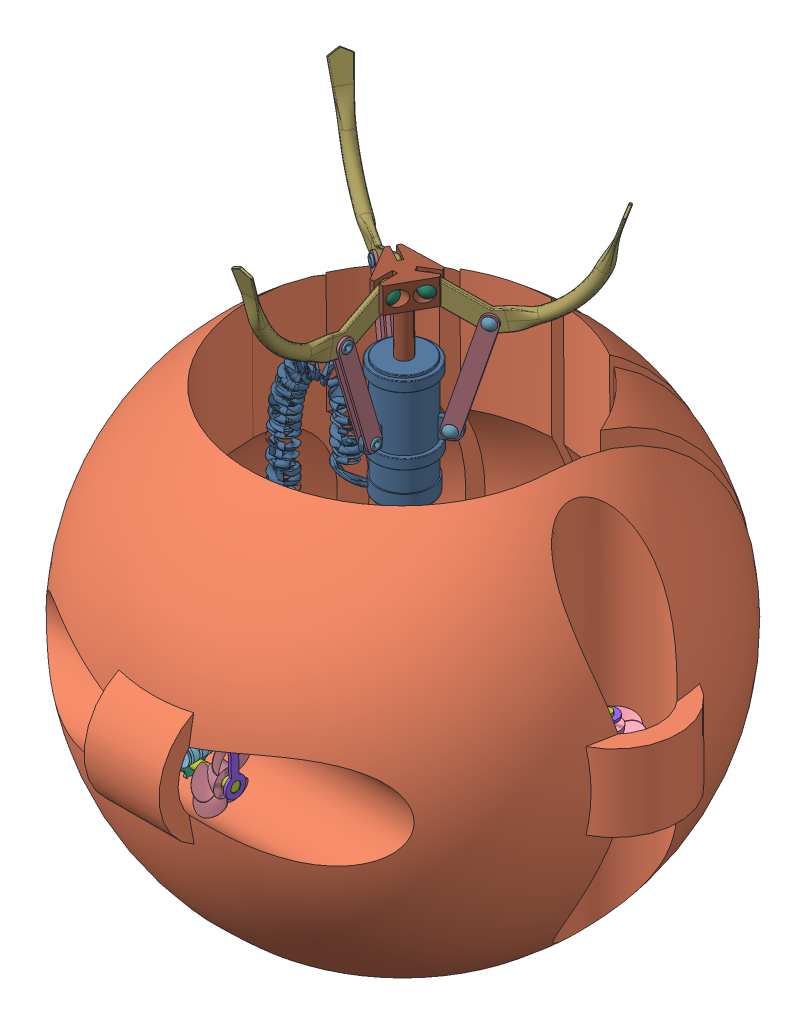
SolidWorks assembly Ensamblaje3, configuration Predeterminado. Lengths in mm.
Overall size (450.55 570.04 429.3).
49 component instances, 15 part files, 26 mates.
Components (placement in the parent):
- Pieza2-1: Pieza2 [Predeterminado] at (-34.488 253.5547 130.2507) x (0.999885 0.01398 -0.005873) z (-0.005729 -0.010275 -0.999931) size (100 100 125)
- esfera-1: esfera [Predeterminado] at (14.9319 234.6332 182.7818) x (0.014039 -0.999849 0.010193) z (0.012601 -0.010017 -0.99987) size (380 440 420)
- Ejes 1-1: Ejes 1 [Predeterminado] at (16.7137 233.883 180.6556) x (0.014039 -0.999849 0.010193) z (0.015814 0.010415 0.999821) size (260 360 184.4)
- Pieza5-1: Pieza5 [Predeterminado] at (36.17 225.0744 353.282) x (0.012182 0.006562 -0.999904) z (0.999904 -0.006643 0.012138) size (49.17 48.96 11.21)
- worm-1: worm [Predeterminado] at (19.7723 236.3191 345.1076) x (0.999875 -0.000209 -0.015813) z (0.015814 0.010415 0.999821) size (16 16.41 26.33)
- gear-1: gear [Predeterminado] at (18.4041 225.247 352.8856) x (0.013028 0.747503 -0.66413) z (0.999904 -0.006643 0.012139) size (19.79 19.79 2)
- Pieza5-2: Pieza5 [Predeterminado] at (-159.6974 247.0657 172.1305) x (0.994038 0.012854 -0.108278) z (-0.014039 0.999849 -0.010193) size (49.17 48.96 11.21)
- Pieza5-3: Pieza5 [Predeterminado] at (188.989 257.8641 195.2969) x (0.817754 0.017348 0.575307) z (0.01404 -0.999849 0.010194) size (49.17 48.96 11.21)
- Pieza5-4: Pieza5 [Predeterminado] at (9.1875 59.5186 198.0938) x (0.986717 0.162088 0.010811) z (-0.0126 0.010017 0.99987) size (49.17 48.96 11.21)
- gear-2: gear [Predeterminado] at (9.1409 59.5957 192.1886) x (0.999921 0.000063 0.012601) z (-0.012601 0.010017 0.99987) size (19.79 19.79 2)
- gear-3: gear [Predeterminado] at (-159.708 233.7543 171.9082) x (0.999805 0.013896 -0.014039) z (0.014039 -0.999849 0.010193) size (19.79 19.79 2)
- gear-4: gear [Predeterminado] at (188.6888 238.5905 194.9996) x (0.999805 0.013896 -0.014039) z (0.014039 -0.999849 0.010193) size (19.79 19.79 2)
- worm-2: worm [Predeterminado] at (181.8244 235.5931 178.8867) x (-0.015758 -0.014382 -0.999772) z (0.999776 0.013876 -0.015958) size (16 16.41 26.33)
- worm-4: worm [Predeterminado] at (-148.8559 232.9027 183.3553) x (0.01593 0.002169 0.999871) z (-0.999776 -0.013876 0.015958) size (16 16.41 26.33)
- worm-5: worm [Predeterminado] at (18.3543 74.6912 183.1674) x (0.848002 0.017308 0.52971) z (0.014039 -0.999849 0.010193) size (16 16.41 26.33)
- mini eje-1: mini eje [Predeterminado] at (188.7869 266.4229 195.1489) x (0.09265 -0.00885 -0.995659) z (0.014039 -0.999849 0.010193) size (8 8 60)
- sujeta mini eje-1: sujeta mini eje [Predeterminado] at (189.066 218.1565 195.1952) x (-0.013575 0.010003 0.999858) z (0.014039 -0.999849 0.010193) size (16 56.94 2)
- sujeta mini eje-2: sujeta mini eje [Predeterminado] at (189.5811 264.863 195.6103) x (0.02299 0.010515 0.99968) z (0.014039 -0.999849 0.010193) size (16 56.94 2)
- sujeta mini eje-3: sujeta mini eje [Predeterminado] at (-159.6349 205.6977 171.876) x (0.026481 -0.000282 -0.999649) z (-0.003497 -0.999994 0.000189) size (16 56.94 2)
- mini eje-2: mini eje [Predeterminado] at (-159.8585 202.3436 171.8952) x (0.901561 -0.003071 0.43264) z (0.003497 0.999994 -0.000189) size (8 8 60)
- sujeta mini eje-4: sujeta mini eje [Predeterminado] at (-159.8363 261.8256 171.9609) x (-0.025639 0.000279 0.999671) z (0.003497 0.999994 -0.000189) size (16 56.94 2)
- mini eje-3: mini eje [Predeterminado] at (9.153 59.6706 153.774) size (8 8 60)
- sujeta mini eje-5: sujeta mini eje [Predeterminado] at (9.2734 59.7371 155.3243) size (16 56.94 2)
- sujeta mini eje-6: sujeta mini eje [Predeterminado] at (9.1464 59.7862 211.2607) size (16 56.94 2)
- bateria-1: bateria [Predeterminado] at (14.3008 144.5079 182.0033) x (0.300394 -0.005506 -0.953799) z (0.014039 -0.999849 0.010193) size (200 200 30)
- mini eje-4: mini eje [Predeterminado] at (-7.5921 225.1294 353.1829) x (-0.004864 -0.442554 -0.896729) z (0.999976 0.002338 -0.006578) size (8 8 60)
- sujeta mini eje-7: sujeta mini eje [Predeterminado] at (-4.8348 225.2894 353.3905) x (-0.006596 0.007693 -0.999949) z (0.999976 0.002338 -0.006578) size (16 56.94 2)
- sujeta mini eje-8: sujeta mini eje [Predeterminado] at (51.0332 225.0668 353.0596) x (-0.006643 0.02898 -0.999558) z (0.999976 0.002338 -0.006578) size (16 56.94 2)
- claw game grabber-1: claw game grabber [Predeterminado] at (16.4487 365.3089 183.0189) x (0.999805 0.013896 -0.014039) z (0.014039 -0.999849 0.010193) size (253.22 219.29 319.04)
  - case-1: case [Predeterminado] at origin size (110.45 77.76 160.33)
  - piston-1: piston [Predeterminado] at (0 0 -92.0003) size (43.11 37.33 100)
  - claw-1: claw [Predeterminado] at (0 14.5 -102.0003) x (1 0 0) z (0 -0.445532 0.895266) size (16.03 91.28 125.86)
  - claw-2: claw [Predeterminado] at (-12.5574 -7.25 -102.0003) x (-0.5 0.866025 0) z (0.385842 0.222766 0.895266) size (16.03 91.28 125.86)
  - claw-3: claw [Predeterminado] at (12.5574 -7.25 -102.0003) x (-0.5 -0.866025 0) z (-0.385842 0.222766 0.895266) size (16.03 91.28 125.86)
  - strut-1: strut [Predeterminado] at (3 27.5 -7.5) x (1 0 0) z (0 -0.285133 0.958488) size (2 12 92)
  - strut-2: strut [Predeterminado] at (-3 27.5 -7.5) x (1 0 0) z (0 -0.285133 0.958488) size (2 12 92)
  - strut-3: strut [Predeterminado] at (22.3157 -16.3481 -7.5) x (-0.5 -0.866025 0) z (-0.246932 0.142566 0.958488) size (2 12 92)
  - strut-4: strut [Predeterminado] at (25.3157 -11.1519 -7.5) x (-0.5 -0.866025 0) z (-0.246932 0.142566 0.958488) size (2 12 92)
  - strut-5: strut [Predeterminado] at (-25.3157 -11.1519 -7.5) x (-0.5 0.866025 0) z (0.246932 0.142566 0.958488) size (2 12 92)
  - strut-6: strut [Predeterminado] at (-22.3157 -16.3481 -7.5) x (-0.5 0.866025 0) z (0.246932 0.142566 0.958488) size (2 12 92)
  - rivet-1: rivet [Predeterminado] at (23.8157 -13.75 -7.5) x (0.866025 -0.5 0) z (0 0 1) size (11.39 14.58 11.86)
  - rivet-2: rivet [Predeterminado] at (43.5703 -25.1553 -84.179) x (0.866025 -0.5 0) z (0 0 1) size (11.39 14.58 11.86)
  - rivet-3: rivet [Predeterminado] at (0 27.5 -7.5) x (0 1 0) z (0 0 1) size (11.39 14.58 11.86)
  - rivet-4: rivet [Predeterminado] at (0 50.3106 -84.179) x (0 1 0) z (0 0 1) size (11.39 14.58 11.86)
  - rivet-5: rivet [Predeterminado] at (-23.8157 -13.75 -7.5) x (-0.866025 -0.5 0) z (0 0 1) size (11.39 14.58 11.86)
  - rivet-6: rivet [Predeterminado] at (-43.5703 -25.1553 -84.179) x (-0.866025 -0.5 0) z (0 0 1) size (11.39 14.58 11.86)
  - rivet_2-1: rivet_2 [Predeterminado] at (0 14.5 -102.0003) size (22.19 14.92 14.32)
  - rivet_2-2: rivet_2 [Predeterminado] at (12.5574 -7.25 -102.0003) x (0.5 0.866025 0) z (0 0 1) size (22.19 14.92 14.32)
  - rivet_2-3: rivet_2 [Predeterminado] at (-12.5574 -7.25 -102.0003) x (0.5 -0.866025 0) z (0 0 1) size (22.19 14.92 14.32)
Mates (geometry in assembly coordinates):
- Paralelo1: parallel aligned: cylinder of Pieza2-1 through (15.7927 254.7674 179.9536) axis (0.014039 -0.999849 0.010193) radius 4; cylinder of Ejes 1-1 through (15.5905 313.871 179.8401) axis (0.014039 -0.999849 0.010193) radius 4
- Paralelo2: parallel anti-aligned: cylinder of esfera-1 through (11.0992 507.5921 179.999) axis (0.014039 -0.999849 0.010193) radius 120; cylinder of Ejes 1-1 through (19.2408 53.9101 182.4904) axis (-0.014039 0.999849 -0.010193) radius 4
- Paralelo3: parallel anti-aligned: cylinder of esfera-1 through (11.0992 507.5921 179.999) axis (0.014039 -0.999849 0.010193) radius 120; cylinder of Ejes 1-1 through (19.2408 53.9101 182.4904) axis (-0.014039 0.999849 -0.010193) radius 4
- Paralelo4: parallel aligned: cylinder of Pieza2-1 through (15.7927 254.7674 179.9536) axis (0.014039 -0.999849 0.010193) radius 4; cylinder of Ejes 1-1 through (15.5905 313.871 179.8401) axis (0.014039 -0.999849 0.010193) radius 4
- Paralelo5: parallel aligned: cylinder of Ejes 1-1 through (19.5603 235.7578 360.6233) axis (-0.015814 -0.010415 -0.999821) radius 4; cylinder of worm-1 through (20.0885 236.5274 365.104) axis (-0.015814 -0.010415 -0.999821) radius 4
- Paralelo6: parallel aligned: cylinder of Pieza5-1 through (46.7728 225.004 353.4107) axis (-0.999904 0.006643 -0.012139) radius 4.2654; cylinder of gear-1 through (20.4039 225.2337 352.9099) axis (-0.999904 0.006643 -0.012139) radius 4
- Paralelo7: parallel aligned: cylinder of Pieza5-1 through (46.7728 225.004 353.4107) axis (-0.999904 0.006643 -0.012139) radius 4.2654; cylinder of gear-1 through (20.4039 225.2337 352.9099) axis (-0.999904 0.006643 -0.012139) radius 4
- Paralelo8: parallel aligned: cylinder of esfera-1 through (-157.8457 432.1949 178.6252) axis (0.014039 -0.999849 0.010193) radius 35; cylinder of Pieza5-2 through (-159.8463 257.668 172.0225) axis (0.014039 -0.999849 0.010193) radius 4.2654
- Paralelo9: parallel anti-aligned: cylinder of esfera-1 through (182.0938 437.0113 182.861) axis (0.014039 -0.999849 0.010193) radius 35; cylinder of Pieza5-3 through (189.1379 247.2619 195.405) axis (-0.014039 0.999849 -0.010193) radius 4.2654
- Paralelo10: parallel aligned: cylinder of esfera-1 through (14.7985 66.6622 384.4888) axis (0.012601 -0.010017 -0.99987) radius 35; cylinder of Pieza5-4 through (9.0539 59.6248 208.6963) axis (0.012601 -0.010017 -0.99987) radius 4.2654
- Paralelo11: parallel aligned: cylinder of esfera-1 through (14.7985 66.6622 384.4888) axis (0.012601 -0.010017 -0.99987) radius 35; cylinder of gear-2 through (9.1157 59.6157 194.1884) axis (0.012601 -0.010017 -0.99987) radius 4
- Paralelo12: parallel anti-aligned: cylinder of esfera-1 through (-157.8457 432.1949 178.6252) axis (0.014039 -0.999849 0.010193) radius 35; cylinder of gear-3 through (-159.6799 231.7546 171.9286) axis (-0.014039 0.999849 -0.010193) radius 4
- Paralelo13: parallel anti-aligned: cylinder of esfera-1 through (182.0938 437.0113 182.861) axis (0.014039 -0.999849 0.010193) radius 35; cylinder of gear-4 through (188.7169 236.5908 195.02) axis (-0.014039 0.999849 -0.010193) radius 4
- Paralelo14: parallel aligned: cylinder of Ejes 1-1 through (196.6734 236.3806 177.7832) axis (-0.999776 -0.013876 0.015958) radius 4.4; cylinder of worm-2 through (201.8199 235.8706 178.5675) axis (-0.999776 -0.013876 0.015958) radius 4
- Paralelo16: parallel anti-aligned: cylinder of Ejes 1-1 through (196.6734 236.3806 177.7832) axis (-0.999776 -0.013876 0.015958) radius 4.4; cylinder of worm-4 through (-168.8515 232.6252 183.6745) axis (0.999776 0.013876 -0.015958) radius 4
- Paralelo17: parallel aligned: cylinder of Pieza2-1 through (15.7927 254.7674 179.9536) axis (0.014039 -0.999849 0.010193) radius 4; cylinder of Ejes 1-1 through (15.5905 313.871 179.8401) axis (0.014039 -0.999849 0.010193) radius 4
- Paralelo18: parallel aligned: cylinder of Ejes 1-1 through (19.2408 53.9101 182.4904) axis (-0.014039 0.999849 -0.010193) radius 4; cylinder of worm-5 through (18.6351 54.6942 183.3713) axis (-0.014039 0.999849 -0.010193) radius 4
- Paralelo19: parallel anti-aligned: cylinder of esfera-1 through (182.0938 437.0113 182.861) axis (0.014039 -0.999849 0.010193) radius 35; cylinder of mini eje-1 through (189.6293 206.4319 195.7605) axis (-0.014039 0.999849 -0.010193) radius 4
- Paralelo20: parallel aligned: cylinder of mini eje-1 through (189.6293 206.4319 195.7605) axis (-0.014039 0.999849 -0.010193) radius 4; cylinder of sujeta mini eje-1 through (189.094 216.1568 195.2156) axis (-0.014039 0.999849 -0.010193) radius 4
- Paralelo21: parallel aligned: cylinder of mini eje-1 through (189.6293 206.4319 195.7605) axis (-0.014039 0.999849 -0.010193) radius 4; cylinder of sujeta mini eje-2 through (189.6092 262.8633 195.6307) axis (-0.014039 0.999849 -0.010193) radius 4
- Paralelo22: parallel aligned: cylinder of mini eje-2 through (-159.6487 262.3433 171.8839) axis (-0.003497 -0.999994 0.000189) radius 4; cylinder of sujeta mini eje-4 through (-159.8293 263.8255 171.9606) axis (-0.003497 -0.999994 0.000189) radius 4
- Paralelo23: parallel anti-aligned: cylinder of sujeta mini eje-3 through (-159.6419 203.6978 171.8764) axis (0.003497 0.999994 -0.000189) radius 4; cylinder of mini eje-2 through (-159.6487 262.3433 171.8839) axis (-0.003497 -0.999994 0.000189) radius 4
- Paralelo24: parallel anti-aligned: cylinder of Ejes 1-1 through (15.5905 313.871 179.8401) axis (0.014039 -0.999849 0.010193) radius 4; cylinder of bateria-1 through (14.722 114.5124 182.3091) axis (-0.014039 0.999849 -0.010193) radius 4
- Paralelo25: parallel aligned: cylinder of mini eje-4 through (52.4065 225.2697 352.7882) axis (-0.999976 -0.002338 0.006578) radius 4; cylinder of sujeta mini eje-8 through (53.0332 225.0715 353.0465) axis (-0.999976 -0.002338 0.006578) radius 4
- Paralelo26: parallel aligned: cylinder of mini eje-4 through (52.4065 225.2697 352.7882) axis (-0.999976 -0.002338 0.006578) radius 4; cylinder of sujeta mini eje-7 through (-2.8348 225.2941 353.3773) axis (-0.999976 -0.002338 0.006578) radius 4
- Paralelo27: parallel aligned: cylinder of Ejes 1-1 through (15.5905 313.871 179.8401) axis (0.014039 -0.999849 0.010193) radius 4; cylinder of claw game grabber-1/case-1 through (16.3809 370.1397 182.9697) axis (0.014039 -0.999849 0.010193) radius 20
